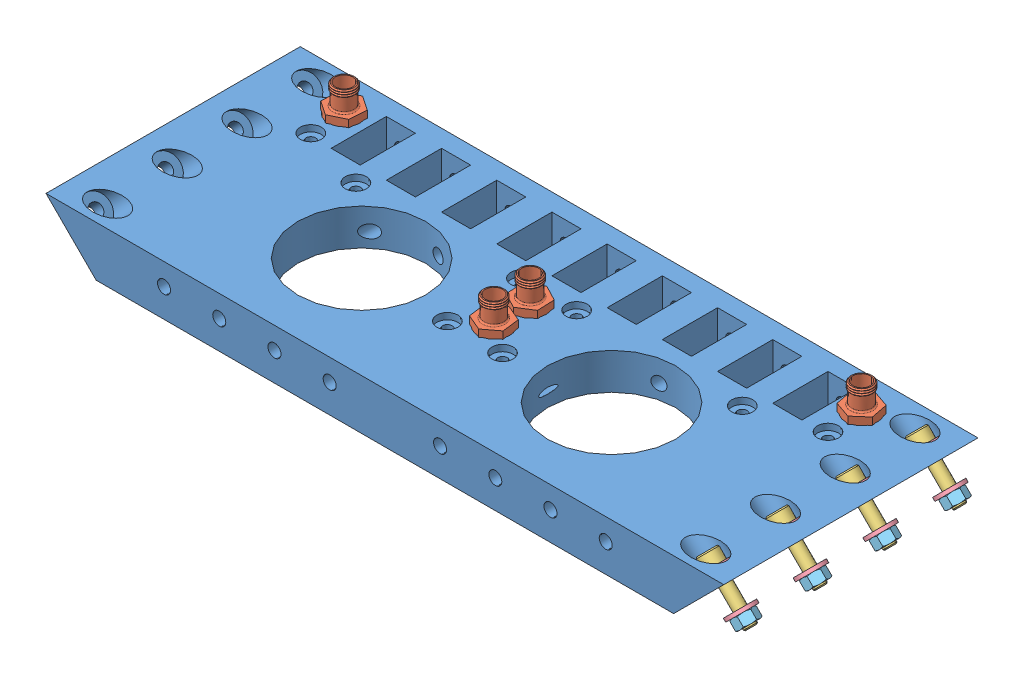
SolidWorks assembly joint_plate_assy_horz_sc_1108, configuration Default. Lengths in mm.
Overall size (476.94 56.8 175).
22 component instances, 5 part files, 11 mates.
Components (placement in the parent):
- joint_plate_horz_sc_1108-1: joint_plate_horz_sc_1108 [Default] at origin size (466.51 34.5 175)
- water_adapter_b_1106-1: water_adapter_b_1106 [Default] at (-178.13 0 25) x (0.899114 0 -0.437714) z (0 1 0) size (24 24 44)
- water_adapter_b_1106-2: water_adapter_b_1106 [Default] at (0 0 75) x (0.84579 0 -0.533515) z (0 1 0) size (24 24 44)
- water_adapter_b_1106-3: water_adapter_b_1106 [Default] at (0 0 100) x (0.797945 0 -0.60273) z (0 1 0) size (24 24 44)
- water_adapter_b_1106-4: water_adapter_b_1106 [Default] at (178.13 0 25) x (0.754239 0 -0.6566) z (0 1 0) size (24 24 44)
- joint_plate_bolts_assy1x48-1: joint_plate_bolts_assy1x48 [Default] at (-0.2085 -212.2842 16) x (0.707107 -0.707107 0) z (0 0 1) size (43 18.8 162.8)
  - Socket Head Cap Screw_AM-1: Socket Head Cap Screw_AM [B18.3.1M - 8 x 1.25 x 35 Hex SHCS -- 35NHX] at (-21 313.5152 0) size (43 13 13)
  - flat washer narrow_am-1: flat washer narrow_am [B18.22M - Plain washer, 8 mm, narrow] at (-10.7 313.5152 0) size (2.3 18.8 18.8)
  - flat washer narrow_am-2: flat washer narrow_am [B18.22M - Plain washer, 8 mm, narrow] at (13.615 313.5152 0) size (2.3 18.8 18.8)
  - Hex Nut Style 1_AM-1: Hex Nut Style 1_AM [B18.2.4.1M - Hex nut, Style 1,  M8 x 1.25 --D-N] at (20.415 313.5152 0) x (0 0 -1) z (1 0 0) size (13 15.01 6.8)
  - Hex Nut Style 1_AM-2: Hex Nut Style 1_AM [B18.2.4.1M - Hex nut, Style 1,  M8 x 1.25 --D-N] at (20.415 313.5152 48) x (0 0 -1) z (1 0 0) size (13 15.01 6.8)
  - Hex Nut Style 1_AM-3: Hex Nut Style 1_AM [B18.2.4.1M - Hex nut, Style 1,  M8 x 1.25 --D-N] at (20.415 313.5152 96) x (0 0 -1) z (1 0 0) size (13 15.01 6.8)
  - Hex Nut Style 1_AM-4: Hex Nut Style 1_AM [B18.2.4.1M - Hex nut, Style 1,  M8 x 1.25 --D-N] at (20.415 313.5152 144) x (0 0 -1) z (1 0 0) size (13 15.01 6.8)
  - flat washer narrow_am-3: flat washer narrow_am [B18.22M - Plain washer, 8 mm, narrow] at (13.615 313.5152 48) size (2.3 18.8 18.8)
  - flat washer narrow_am-4: flat washer narrow_am [B18.22M - Plain washer, 8 mm, narrow] at (13.615 313.5152 96) size (2.3 18.8 18.8)
  - flat washer narrow_am-5: flat washer narrow_am [B18.22M - Plain washer, 8 mm, narrow] at (13.615 313.5152 144) size (2.3 18.8 18.8)
  - flat washer narrow_am-6: flat washer narrow_am [B18.22M - Plain washer, 8 mm, narrow] at (-10.7 313.5152 48) size (2.3 18.8 18.8)
  - flat washer narrow_am-7: flat washer narrow_am [B18.22M - Plain washer, 8 mm, narrow] at (-10.7 313.5152 96) size (2.3 18.8 18.8)
  - flat washer narrow_am-8: flat washer narrow_am [B18.22M - Plain washer, 8 mm, narrow] at (-10.7 313.5152 144) size (2.3 18.8 18.8)
  - Socket Head Cap Screw_AM-2: Socket Head Cap Screw_AM [B18.3.1M - 8 x 1.25 x 35 Hex SHCS -- 35NHX] at (-21 313.5152 48) size (43 13 13)
  - Socket Head Cap Screw_AM-3: Socket Head Cap Screw_AM [B18.3.1M - 8 x 1.25 x 35 Hex SHCS -- 35NHX] at (-21 313.5152 96) size (43 13 13)
  - Socket Head Cap Screw_AM-4: Socket Head Cap Screw_AM [B18.3.1M - 8 x 1.25 x 35 Hex SHCS -- 35NHX] at (-21 313.5152 144) size (43 13 13)
Mates (geometry in assembly coordinates):
- Concentric1: concentric anti-aligned: cylinder of joint_plate_horz_sc_1108-1 through (-178.13 25 25) axis (0 1 0) radius 11; cylinder of water_adapter_b_1106-1 through (-178.13 30 25) axis (0 -1 0) radius 12
- Concentric2: concentric anti-aligned: cylinder of joint_plate_horz_sc_1108-1 through (0 25 75) axis (0 1 0) radius 11; cylinder of water_adapter_b_1106-2 through (0 30 75) axis (0 -1 0) radius 12
- Concentric3: concentric anti-aligned: cylinder of joint_plate_horz_sc_1108-1 through (0 25 100) axis (0 1 0) radius 11; cylinder of water_adapter_b_1106-3 through (0 30 100) axis (0 -1 0) radius 12
- Concentric4: concentric anti-aligned: cylinder of joint_plate_horz_sc_1108-1 through (178.13 25 25) axis (0 1 0) radius 11; cylinder of water_adapter_b_1106-4 through (178.13 30 25) axis (0 -1 0) radius 12
- Coincident1: coincident aligned: plane of joint_plate_horz_sc_1108-1 through (-208.2574 0 125) normal (0 -1 0); plane of water_adapter_b_1106-1 through (-178.13 0 25) normal (0 -1 0)
- Coincident2: coincident aligned: plane of joint_plate_horz_sc_1108-1 through (-208.2574 0 125) normal (0 -1 0); plane of water_adapter_b_1106-3 through (0 0 100) normal (0 -1 0)
- Coincident3: coincident aligned: plane of joint_plate_horz_sc_1108-1 through (-208.2574 0 125) normal (0 -1 0); plane of water_adapter_b_1106-2 through (0 0 75) normal (0 -1 0)
- Coincident4: coincident aligned: plane of joint_plate_horz_sc_1108-1 through (-208.2574 0 125) normal (0 -1 0); plane of water_adapter_b_1106-4 through (178.13 0 25) normal (0 -1 0)
- Coincident5: coincident anti-aligned: plane of joint_plate_horz_sc_1108-1 through (213.9142 16.9706 64) normal (-0.707107 0.707107 0); plane of joint_plate_bolts_assy1x48-1/flat washer narrow_am-6 through (217.1386 20.195 64) normal (0.707107 -0.707107 0)
- Concentric5: concentric anti-aligned: cylinder of joint_plate_horz_sc_1108-1 through (-13.6863 244.5711 160) axis (0.707107 -0.707107 0) radius 4.5; cylinder of joint_plate_bolts_assy1x48-1/Socket Head Cap Screw_AM-4 through (184.1804 46.7044 160) axis (-0.707107 0.707107 0) radius 4
- Concentric6: concentric anti-aligned: cylinder of joint_plate_horz_sc_1108-1 through (-13.6863 244.5711 16) axis (0.707107 -0.707107 0) radius 4.5; cylinder of joint_plate_bolts_assy1x48-1/Socket Head Cap Screw_AM-1 through (184.1804 46.7044 16) axis (-0.707107 0.707107 0) radius 4
